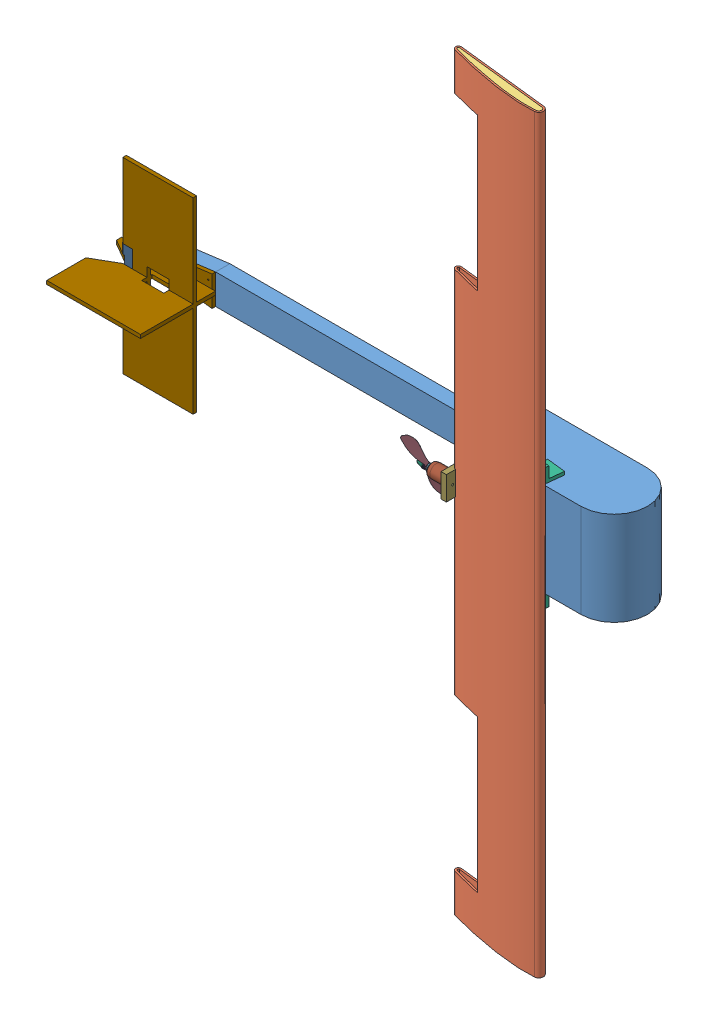
SolidWorks assembly Assembly for Gazebo, configuration Default. Lengths in mm.
Overall size (1443.84 2000 247.62).
39 component instances, 17 part files, 18 mates.
Components (placement in the parent):
- Main-Body-Final-2: Main-Body-Final [Default] x (-1 0 0) z (0 0 -1) size (1434.84 250 177.38)
- Wing_Assembly-2: Wing_Assembly [Default] at (373.7329 -1603.0021 -901.421) x (-1 0 0.000004) z (0 1 0) size (266.58 103.25 2000)
  - Wing_Shell-1: Wing_Shell [Default] at (572.5773 1078.9916 1603.0021) size (266.58 52.82 2000)
  - Wing_Strut-1: Wing_Strut [Default] at (572.5773 1078.9916 1770.3583) size (257.05 45.8 14.29)
  - Wing_Strut-2: Wing_Strut [Default] at (572.5773 1078.9916 1435.6458) size (257.05 45.8 14.29)
  - Wing_Strut-3: Wing_Strut [Default] at (572.5773 1078.9916 1168.9458) size (257.05 45.8 14.29)
  - Wing_Strut-4: Wing_Strut [Default] at (572.5773 1078.9916 2037.0583) size (257.05 45.8 14.29)
  - Wing_Strut-5: Wing_Strut [Default] at (572.5773 1078.9916 2595.8583) size (257.05 45.8 14.29)
  - Wing_Strut-6: Wing_Strut [Default] at (572.5773 1078.9916 610.1458) size (257.05 45.8 14.29)
  - Wing_Strut-7: Wing_Strut [Default] at (572.5773 1078.9916 1910.0583) size (257.05 45.8 14.29)
  - Wing_Strut-8: Wing_Strut [Aileron_Strut] at (572.5773 1078.9916 914.9458) size (179.71 35.09 14.29)
  - Wing_Strut-9: Wing_Strut [Default] at (572.5773 1078.9916 1295.9458) size (257.05 45.8 14.29)
  - Wing_Strut-10: Wing_Strut [Aileron_Strut] at (572.5773 1078.9916 2291.0583) size (179.71 35.09 14.29)
  - Wing_to_Aileron-1: Wing_to_Aileron [Default] at (584.7979 1071.237 2202.9521) x (0 0 -1) z (0.99387 -0.110554 0) size (63.5 15 63.5)
  - Wing_to_Aileron-2: Wing_to_Aileron [Default] at (581.0212 1071.6571 2393.4521) x (0 0 -1) z (0.99387 -0.110554 0) size (63.5 15 63.5)
  - Wing_to_Aileron_Dowel-1: Wing_to_Aileron_Dowel [Default] at (642.4267 1072.3729 2202.9521) x (-0.99387 0.110554 0) z (0 0 -1) size (5.2 5.2 63.5)
  - Wing_to_Aileron_Dowel-2: Wing_to_Aileron_Dowel [Default] at (638.65 1072.793 2393.4521) x (-0.988983 -0.148032 0) z (0 0 -1) size (5.2 5.2 63.5)
  - Wing_to_Aileron-3: Wing_to_Aileron [Default] at (584.7979 1071.237 1003.0521) x (0 0 -1) z (0.99387 -0.110554 0) size (63.5 15 63.5)
  - Wing_to_Aileron-4: Wing_to_Aileron [Default] at (581.0212 1071.6571 812.5521) x (0 0 -1) z (0.99387 -0.110554 0) size (63.5 15 63.5)
  - Wing_to_Aileron_Dowel-3: Wing_to_Aileron_Dowel [Default] at (642.4267 1072.3729 1003.0521) x (0.875718 -0.482823 0) z (0 0 1) size (5.2 5.2 63.5)
  - Wing_to_Aileron_Dowel-4: Wing_to_Aileron_Dowel [Default] at (638.65 1072.793 812.5521) x (0.875718 -0.482823 0) z (0 0 1) size (5.2 5.2 63.5)
  - Wing_to_Fuselage-5: Wing_to_Fuselage [Default] at (694.3922 1054.2543 1458.9521) x (0.99387 -0.110554 0) z (-0.110554 -0.99387 0) size (50.8 50.8 50.8)
  - Wing_to_Fuselage-6: Wing_to_Fuselage [Default] at (498.9791 1075.9912 1747.0521) x (-0.99387 0.110554 0) z (-0.110554 -0.99387 0) size (50.8 50.8 50.8)
  - Wing_to_Fuselage-7: Wing_to_Fuselage [Default] at (694.3922 1054.2543 1747.0521) x (-0.99387 0.110554 0) z (-0.110554 -0.99387 0) size (50.8 50.8 50.8)
  - Wing_to_Fuselage-8: Wing_to_Fuselage [Default] at (498.9791 1075.9912 1458.9521) x (0.99387 -0.110554 0) z (-0.110554 -0.99387 0) size (50.8 50.8 50.8)
  - Aileron_Servo_Mount-1: Aileron_Servo_Mount [Default] at (550.0454 1085.1644 959.9471) x (-0.99387 0.110554 0) z (0 0 -1) size (72.55 21 30)
  - Aileron_Servo_Mount-2: Aileron_Servo_Mount [Default] at (550.1007 1085.6613 2246.0571) x (0.99387 -0.110554 0) z (0 0 1) size (72.55 21 30)
  - Aileron_Servo-1: Aileron_Servo [Default] at (550.0454 1085.1644 929.9471) x (-0.99387 0.110554 0) z (0 0 1) size (54.5 20 44)
  - Aileron_Servo-2: Aileron_Servo [Default] at (550.0454 1085.1644 2276.0571) x (-0.99387 0.110554 0) z (0 0 -1) size (54.5 20 44)
- Tail_Non_Removeable-2: Tail_Non_Removeable [Default] at (-1230.15 0 38.1) x (0 -1 0) z (0 0 1) size (500 250 221.53)
- Tail-to-Elevator-2: Tail-to-Elevator [Default] at (-1279.95 0 98.4188) x (0 -1 0) z (0 0 1) size (101.6 29.37 7.94)
- Turnigy Motor-2: Turnigy Motor [Default] at (-369.4375 0 163.83) x (0 0 1) z (-1 0 0) size (35.77 35.77 64.04)
- Motor Mount-2: Motor Mount [Default] at (-360.4375 0 114.3) x (0 1 0) z (1 0 0) size (63.5 152.4 14.29)
- Propeller_Assembly-1: Propeller_Assembly [Default] at (-292.7637 217.0966 149.7938) x (0 -0.371305 0.928511) z (0 -0.928511 -0.371305) size (60.03 39.31 246.43)
  - 10x4.7-1: 10x4.7 [Default] at (88.6419 126.1738 192.5649) size (60.03 10.54 246.43)
  - Prop_Bottom_Grip-1: Prop_Bottom_Grip [Default] at (93.6419 125.6738 196.3649) x (1 0 0) z (0 -1 0) size (17 17 8)
  - Prop_End_Cap-1: Prop_End_Cap [Default] at (93.6419 135.4738 196.3649) x (0.336443 0 -0.941704) z (0 1 0) size (18 18 21.5)
  - Prop_Shaft_Clamp-1: Prop_Shaft_Clamp [Default] at (93.6419 117.6738 196.3649) x (1 0 0) z (0 1 0) size (11.03 11.03 33.01)
  - Prop_Top_Grip-1: Prop_Top_Grip [Default] at (93.6419 132.3738 196.3649) x (1 0 0) z (0 1 0) size (17 17 3.1)
Mates (geometry in assembly coordinates):
- Coincident19: coincident: point of Main-Body-Final-2
- Coincident20: coincident anti-aligned: plane of Main-Body-Final-2 through (-346.15 125 150) normal (-0.11055 0 0.993871); plane of Wing_Assembly-2/Wing_Shell-1 through (-99.9981 1000 177.38) normal (0.11055 0 -0.993871)
- Coincident21: coincident anti-aligned: plane of Main-Body-Final-2 through (0 -125 88.69) normal (0 -1 0); plane of Wing_Assembly-2/Wing_to_Fuselage-8 through (-98.5941 -125 164.7578) normal (0 1 0)
- Coincident22: coincident anti-aligned: line of Main-Body-Final-2 through (-99.9981 -115.475 177.38) axis (0 1 0); line of Wing_Assembly-2/Wing_Shell-1 through (-99.9981 1000 177.38) axis (0 -1 0)
- Coincident23: coincident anti-aligned: plane of Main-Body-Final-2 through (-1114.15 40 38.1) normal (0 0 1); plane of Tail_Non_Removeable-2 through (-1230.15 0 38.1) normal (0 0 -1)
- Width9: width aligned: plane of Main-Body-Final-2 through (-1326.15 -2.3813 25.4) normal (0 1 0); plane of Tail_Non_Removeable-2 through (-1326.15 2.3813 25.4) normal (0 -1 0); plane of Main-Body-Final-2 through (-1135.15 2.35 26.1) normal (0 1 0); plane of Tail_Non_Removeable-2 through (-1135.15 -2.35 26.1) normal (0 -1 0)
- Width10: width anti-aligned: plane of Main-Body-Final-2 through (-1134.15 2.3813 25.4) normal (-1 0 0); plane of Tail_Non_Removeable-2 through (-1326.15 2.3813 25.4) normal (1 0 0); plane of Main-Body-Final-2 through (-1105.15 4.7625 97.625) normal (1 0 0); plane of Tail_Non_Removeable-2 through (-1355.15 4.7625 97.625) normal (-1 0 0)
- Width11: width anti-aligned: plane of Tail-to-Elevator-2 through (-1267.25 50.8 106.3563) normal (0 1 0); plane of Tail_Non_Removeable-2 through (-1267.25 -50.8 106.3563) normal (0 -1 0); plane of Tail-to-Elevator-2 through (-1267.25 50.8 107.15) normal (0 -1 0); plane of Tail_Non_Removeable-2 through (-1267.25 -50.8 107.15) normal (0 1 0)
- Width12: width aligned: plane of Tail-to-Elevator-2 through (-1279.95 0 106.3563) normal (0 0 1); plane of Tail_Non_Removeable-2 through (-1279.95 0 98.4188) normal (0 0 -1); plane of Tail-to-Elevator-2 through (-1230.15 0 107.15) normal (0 0 1); plane of Tail_Non_Removeable-2 through (-1230.15 0 97.625) normal (0 0 -1)
- Coincident24: coincident anti-aligned: plane of Tail_Non_Removeable-2 through (-1267.25 0 38.1) normal (-1 0 0); plane of Tail-to-Elevator-2 through (-1267.25 50.8 106.3563) normal (1 0 0)
- Coincident25: coincident anti-aligned: plane of Main-Body-Final-2 through (-346.15 125 150) normal (-1 0 0); plane of Motor Mount-2 through (-346.15 0 114.3) normal (1 0 0)
- Width14: width anti-aligned: plane of Main-Body-Final-2 through (0 125 88.69) normal (0 1 0); plane of Motor Mount-2 through (0 -125 88.69) normal (0 -1 0); plane of Main-Body-Final-2 through (-346.15 -31.75 190.5) normal (0 -1 0); plane of Motor Mount-2 through (-346.15 31.75 190.5) normal (0 1 0)
- Coincident26: coincident anti-aligned: plane of Main-Body-Final-2 through (-1114.15 40 38.1) normal (0 0 1); plane of Motor Mount-2 through (-346.15 -31.75 38.1) normal (0 0 -1)
- Concentric6: concentric aligned: cylinder of Turnigy Motor-2 through (-360.4375 -12.5 163.83) axis (1 0 0) radius 1.7; cylinder of Motor Mount-2 through (-360.4375 -12.5 163.83) axis (1 0 0) radius 2.5
- Concentric8: concentric aligned: cylinder of Turnigy Motor-2 through (-360.4375 12.5 163.83) axis (1 0 0) radius 1.7; cylinder of Motor Mount-2 through (-360.4375 12.5 163.83) axis (1 0 0) radius 2.5
- Coincident27: coincident anti-aligned: plane of Turnigy Motor-2 through (-360.4375 0 163.83) normal (1 0 0); plane of Motor Mount-2 through (-360.4375 0 114.3) normal (-1 0 0)
- Concentric9: concentric aligned: cylinder of Turnigy Motor-2 through (-424.4375 0 163.83) axis (1 0 0) radius 2.5; cylinder of Propeller_Assembly-1/Prop_Shaft_Clamp-1 through (-424.4375 0 163.83) axis (1 0 0) radius 2.5
- Coincident28: coincident anti-aligned: circle of Turnigy Motor-2; circle of Propeller_Assembly-1/Prop_Shaft_Clamp-1
